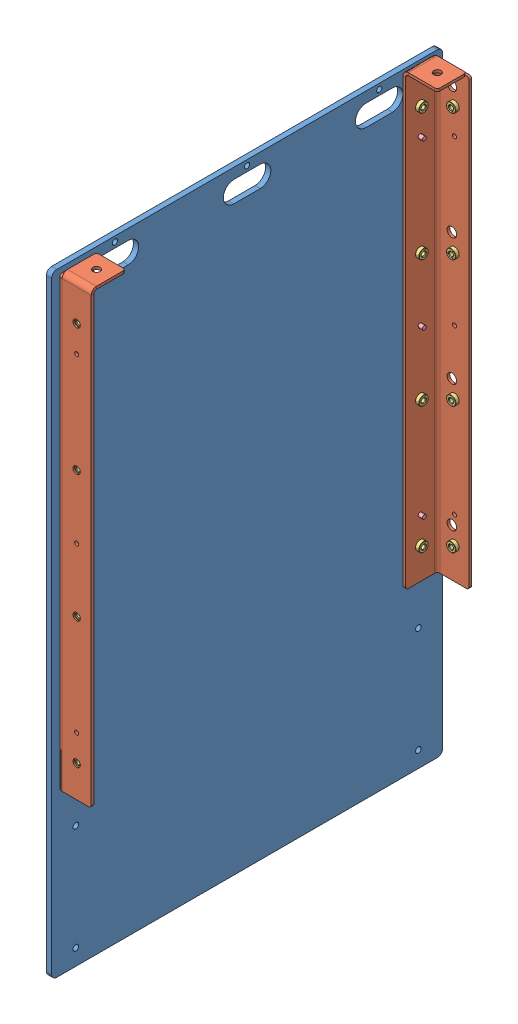
SolidWorks assembly GE-25104, configuration Default. Lengths in mm.
Overall size (49.23 736.6 469.9).
27 component instances, 4 part files, 11 mates.
Components (placement in the parent):
- GE-25105-1: GE-25105 [Default] at (0 368.3 234.95) size (6.35 736.6 469.9)
- GE-25106-1: GE-25106 [Default] at (6.35 736.6 6.35) size (41.27 540 41.27)
  - GE-25106-01-1: GE-25106-01 [Above ramp] at (3.175 -273.304 3.175) size (41.27 540 41.27)
  - pem_clinchnut_.25_20_.054-1: pem_clinchnut_.25_20_.054 [Default] at (1.8034 -44.45 23.8125) size (5.69 11.18 11.18)
  - pem_clinchnut_.25_20_.054-2: pem_clinchnut_.25_20_.054 [Default] at (23.8125 -44.704 1.8034) x (0 0 1) z (-1 0 0) size (5.69 11.18 11.18)
  - pem_clinchnut_.25_20_.054-3: pem_clinchnut_.25_20_.054 [Default] at (23.8125 -197.104 1.8034) x (0 0 1) z (-1 0 0) size (5.69 11.18 11.18)
  - pem_clinchnut_.25_20_.054-4: pem_clinchnut_.25_20_.054 [Default] at (1.8034 -196.9347 23.8125) size (5.69 11.18 11.18)
  - pem_clinchnut_.25_20_.054-5: pem_clinchnut_.25_20_.054 [Default] at (23.8125 -349.504 1.8034) x (0 0 1) z (-1 0 0) size (5.69 11.18 11.18)
  - pem_clinchnut_.25_20_.054-6: pem_clinchnut_.25_20_.054 [Default] at (1.8034 -349.4193 23.8125) size (5.69 11.18 11.18)
  - pem_clinchnut_.25_20_.054-7: pem_clinchnut_.25_20_.054 [Default] at (23.8125 -501.904 1.8034) x (0 0 1) z (-1 0 0) size (5.69 11.18 11.18)
  - pem_clinchnut_.25_20_.054-8: pem_clinchnut_.25_20_.054 [Default] at (1.8034 -501.904 23.8125) size (5.69 11.18 11.18)
- GE-25106-2: GE-25106 [Default] at (6.35 736.6 463.55) x (0 0 -1) z (1 0 0) size (41.27 540 41.27)
  - GE-25106-01-1: GE-25106-01 [Above ramp] at (3.175 -273.304 3.175) size (41.27 540 41.27)
  - pem_clinchnut_.25_20_.054-1: pem_clinchnut_.25_20_.054 [Default] at (1.8034 -44.45 23.8125) size (5.69 11.18 11.18)
  - pem_clinchnut_.25_20_.054-2: pem_clinchnut_.25_20_.054 [Default] at (23.8125 -44.704 1.8034) x (0 0 1) z (-1 0 0) size (5.69 11.18 11.18)
  - pem_clinchnut_.25_20_.054-3: pem_clinchnut_.25_20_.054 [Default] at (23.8125 -197.104 1.8034) x (0 0 1) z (-1 0 0) size (5.69 11.18 11.18)
  - pem_clinchnut_.25_20_.054-4: pem_clinchnut_.25_20_.054 [Default] at (1.8034 -196.9347 23.8125) size (5.69 11.18 11.18)
  - pem_clinchnut_.25_20_.054-5: pem_clinchnut_.25_20_.054 [Default] at (23.8125 -349.504 1.8034) x (0 0 1) z (-1 0 0) size (5.69 11.18 11.18)
  - pem_clinchnut_.25_20_.054-6: pem_clinchnut_.25_20_.054 [Default] at (1.8034 -349.4193 23.8125) size (5.69 11.18 11.18)
  - pem_clinchnut_.25_20_.054-7: pem_clinchnut_.25_20_.054 [Default] at (23.8125 -501.904 1.8034) x (0 0 1) z (-1 0 0) size (5.69 11.18 11.18)
  - pem_clinchnut_.25_20_.054-8: pem_clinchnut_.25_20_.054 [Default] at (1.8034 -501.904 23.8125) size (5.69 11.18 11.18)
- rivet_.1875_.251-.375-1: rivet_.1875_.251-.375 [Default] at (0 660.146 439.7375) x (0 0 1) z (-1 0 0) size (10.01 10.01 16.21)
- rivet_.1875_.251-.375-2: rivet_.1875_.251-.375 [Default] at (0 660.146 30.1625) x (0 0 1) z (-1 0 0) size (10.01 10.01 16.21)
- rivet_.1875_.251-.375-3: rivet_.1875_.251-.375 [Default] at (0 463.296 439.7375) x (0 0 1) z (-1 0 0) size (10.01 10.01 16.21)
- rivet_.1875_.251-.375-4: rivet_.1875_.251-.375 [Default] at (0 463.296 30.1625) x (0 0 1) z (-1 0 0) size (10.01 10.01 16.21)
- rivet_.1875_.251-.375-5: rivet_.1875_.251-.375 [Default] at (0 266.446 439.7375) x (0 0 1) z (-1 0 0) size (10.01 10.01 16.21)
- rivet_.1875_.251-.375-6: rivet_.1875_.251-.375 [Default] at (0 266.446 30.1625) x (0 0 1) z (-1 0 0) size (10.01 10.01 16.21)
Mates (geometry in assembly coordinates):
- Coincident1: coincident anti-aligned: plane of GE-25105-1 through (6.35 0 469.9) normal (0 -1 0)
- Coincident2: coincident anti-aligned: plane of GE-25105-1 through (0 368.3 234.95) normal (-1 0 0)
- Coincident3: coincident anti-aligned: plane of GE-25105-1 through (6.35 0 0) normal (0 0 -1)
- Coincident37: coincident aligned: plane of GE-25105-1 through (6.35 736.6 469.9) normal (0 1 0); plane of Corner Channel Assem-1/ramp_innercornerbracket_plasticplastic-1 through (9.525 736.6 9.525) normal (0 1 0)
- Coincident38: coincident anti-aligned: plane of GE-25105-1 through (6.35 368.3 234.95) normal (1 0 0); plane of Corner Channel Assem-1/ramp_innercornerbracket_plasticplastic-1 through (6.35 729.996 9.525) normal (-1 0 0)
- Distance4: distance = 6.35 mm aligned: plane of Corner Channel Assem-1/ramp_innercornerbracket_plasticplastic-1 through (47.625 729.996 6.35) normal (0 0 -1); plane of GE-25105-1 through (6.35 0 0) normal (0 0 -1)
- Coincident40: coincident anti-aligned: plane of GE-25105-1 through (6.35 368.3 234.95) normal (1 0 0); plane of Corner Channel Assem-2/ramp_innercornerbracket_plasticplastic-1 through (6.35 729.996 422.275) normal (-1 0 0)
- Concentric30: concentric aligned: cylinder of GE-25105-1 through (6.35 660.146 439.7375) axis (1 0 0) radius 2.4574; cylinder of Corner Channel Assem-2/ramp_innercornerbracket_plasticplastic-1 through (9.525 660.146 439.7375) axis (1 0 0) radius 2.4574
- Concentric31: concentric aligned: cylinder of GE-25105-1 through (6.35 266.446 439.7375) axis (1 0 0) radius 2.4574; cylinder of Corner Channel Assem-2/ramp_innercornerbracket_plasticplastic-1 through (9.525 266.446 439.7375) axis (1 0 0) radius 2.4574
- Concentric32: concentric anti-aligned: cylinder of GE-25105-1 through (6.35 660.146 439.7375) axis (1 0 0) radius 2.4574; cylinder of rivet_.1875_.251-.375-1 through (14.605 660.146 439.7375) axis (-1 0 0) radius 2.3813
- Coincident41: coincident anti-aligned: plane of GE-25105-1 through (0 368.3 234.95) normal (-1 0 0); plane of rivet_.1875_.251-.375-1 through (0 660.146 439.7375) normal (1 0 0)
